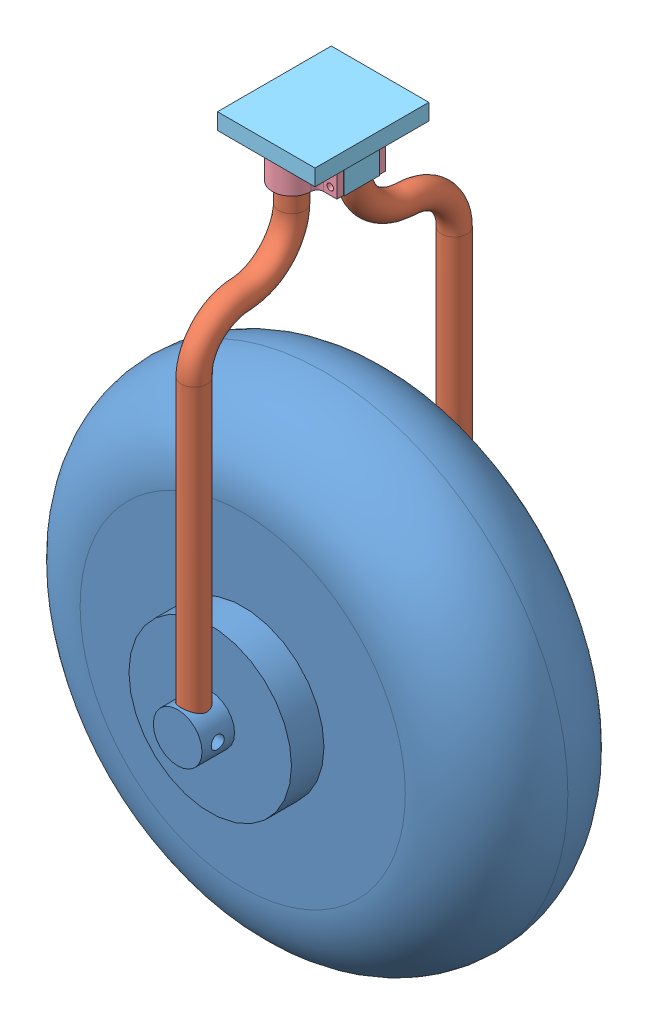
SolidWorks assembly iniştakımımontaj, configuration Varsayılan. Lengths in mm.
Overall size (150 220.34 90).
8 component instances, 5 part files, 19 mates.
Components (placement in the parent):
- teker-2: teker [Varsayılan] at (92.7809 56.775 139.8234) x (0 0 -1) z (1 0 0) size (90 150 150)
- tekertutacağı-2: tekertutacağı [Varsayılan] at (92.8309 50.4307 74.8234) x (0.999818 0 0.019092) z (-0.019092 0 0.999818) size (8.24 145.59 38.73)
- tejerpim-1: tejerpim [Varsayılan] at (85.2809 56.775 74.6287) size (10 4 4)
- tekertutacağı-5: tekertutacağı [Varsayılan] at (92.8309 50.4307 154.8234) x (-0.999818 0 0.019092) z (-0.019092 0 -0.999818) size (8.24 145.59 38.73)
- tejerpim-2: tejerpim [Varsayılan] at (85.2943 56.7751 154.9877) x (0.998574 0.052016 -0.011999) z (0.011999 0.000312 0.999928) size (10 4 4)
- tekermenteşe-3: tekermenteşe [Varsayılan] at (92.2467 187.1158 105.4212) size (23.88 9 9.86)
- tekermenteşe-4: tekermenteşe [Varsayılan] at (92.2467 187.1158 124.2256) x (-1 0 0) z (0 0 -1) size (23.88 9 9.86)
- sapbağlantı-3: sapbağlantı [Varsayılan] at (92.5209 187.1158 114.824) size (30 15 35)
Mates (geometry in assembly coordinates):
- Teğet9: tangent: curve of teker-2; circle of tekertutacağı-2
- Paralel1: parallel: cylinder of teker-2 through (92.7809 66.775 74.8234) axis (0 -1 0) radius 4; cylinder of tekertutacağı-2 through (92.8309 150.4307 74.8234) axis (0 -1 0) radius 3.95
- Eş Merkezli4: concentric: cylinder of teker-2 through (102.7809 56.775 74.6287) axis (-1 0 0) radius 2; cylinder of tejerpim-1 through (95.2809 56.775 74.6287) axis (-1 0 0) radius 2
- Teğet10: tangent: curve of teker-2; circle of tejerpim-1
- Teğet18: tangent: curve of teker-2; circle of tekertutacağı-5
- Paralel6: parallel: cylinder of teker-2 through (92.7809 66.775 154.8234) axis (0 -1 0) radius 4; cylinder of tekertutacağı-5 through (92.8309 150.4307 154.8234) axis (0 -1 0) radius 3.95
- Teğet19: tangent: curve of teker-2; circle of tejerpim-2
- Kilitle4: lock: unknown of teker-2; unknown of tejerpim-2
- Kilitle5: lock: unknown of teker-2; unknown of tejerpim-1
- Eş Merkezli6: concentric: circle of tekertutacağı-2; circle of tekermenteşe-3
- Eş Merkezli7: concentric: circle of tekertutacağı-5; circle of tekermenteşe-4
- Eş Merkezli8: concentric: cylinder of tekermenteşe-3 through (82.3324 193.8658 116.392) axis (0 0 -1) radius 1; cylinder of tekermenteşe-4 through (82.3324 193.8658 113.2548) axis (0 0 1) radius 1
- Kilitle6: lock: unknown of tekermenteşe-3; unknown of tekermenteşe-4
- Kilitle8: lock: unknown of tekertutacağı-2; unknown of tekermenteşe-3
- Kilitle9: lock: unknown of tekertutacağı-5; unknown of tekermenteşe-4
- Çakışık13: coincident: plane of tekermenteşe-4 through (97.9996 196.1158 120.284) normal (0 0 -1); plane of sapbağlantı-3 through (80.5809 197.1158 120.284) normal (0 0 1)
- Çakışık14: coincident: plane of tekermenteşe-3 through (86.329 187.1158 107.392) normal (0 -1 0); plane of sapbağlantı-3 through (92.5209 187.1158 114.824) normal (0 -1 0)
- Eş Merkezli10: concentric: cylinder of tekermenteşe-4 through (102.1609 189.3658 113.2548) axis (0 0 1) radius 1; cylinder of sapbağlantı-3 through (102.1609 189.3658 117.284) axis (0 0 1) radius 1
- Kilitle11: lock: unknown of tekermenteşe-4; unknown of sapbağlantı-3
